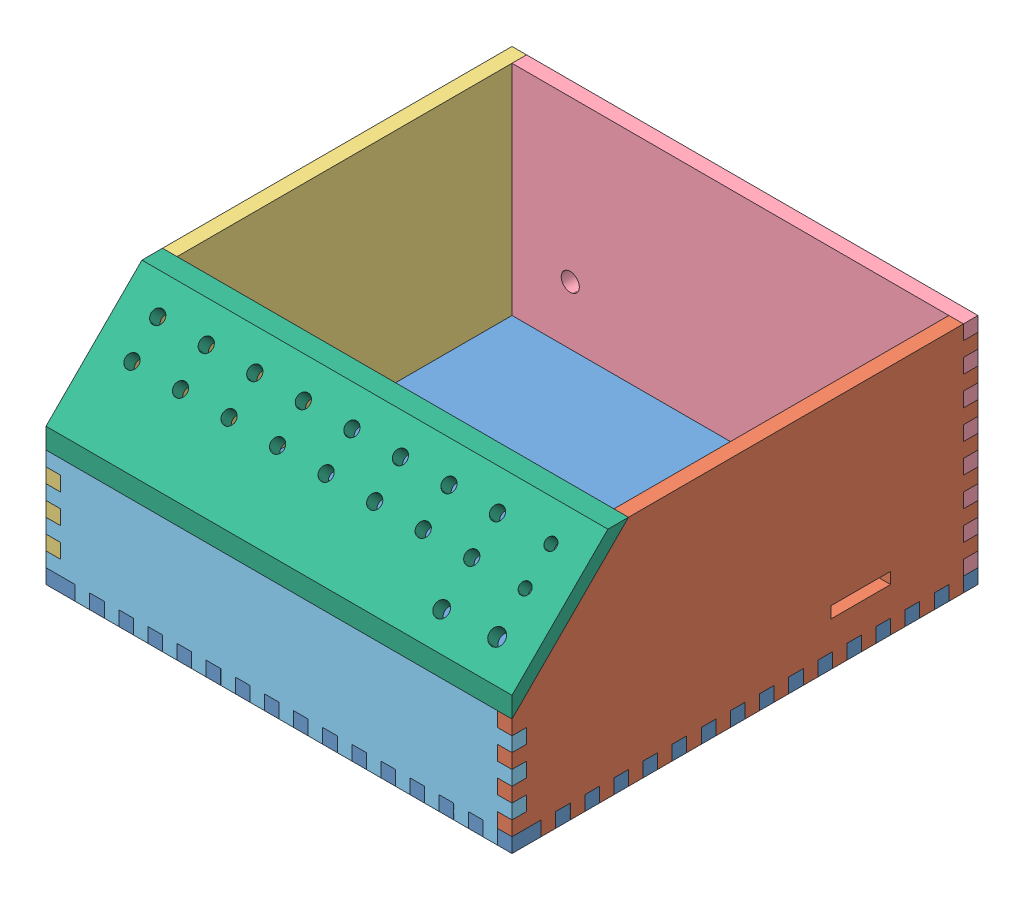
SolidWorks assembly Z80 Box_assembly, configuration Default. Lengths in mm.
Overall size (203.2 106.09 207.69).
6 component instances, 6 part files, 9 mates.
Components (placement in the parent):
- Z80 Box_base-1: Z80 Box_base [Default] at (-24.3287 94.5971 262.4406) size (203.2 6.35 203.2)
- Z80 Box_side_right-1: Z80 Box_side_right [Default] at (172.5213 94.5971 262.4406) size (6.35 101.6 203.2)
- Z80 Box_side_left-1: Z80 Box_side_left [Default] at (-17.9787 94.5971 262.4406) size (6.35 101.6 203.2)
- Z80 Box_back-1: Z80 Box_back [Default] at (178.8713 94.5971 65.5906) x (0 0 -1) z (1 0 0) size (6.35 101.6 203.2)
- Z80 Box_front_bottom-1: Z80 Box_front_bottom [Default] at (-24.3287 94.5971 256.0906) size (203.2 57.15 6.35)
- Z80 Box_front_top-2: Z80 Box_front_top [Default] at (-24.3287 145.3971 262.4406) x (1 0 0) z (0 0.707107 0.707107) size (203.2 71.84 6.35)
Mates (geometry in assembly coordinates):
- Coincident1: coincident aligned: line of Z80 Box_base-1 through (178.8713 100.9471 262.4406) axis (-1 0 0); line of Z80 Box_side_right-1 through (178.8713 100.9471 262.4406) axis (-1 0 0)
- Coincident2: coincident anti-aligned: line of Z80 Box_base-1 through (178.8713 94.5971 249.7406) axis (0 1 0); line of Z80 Box_side_right-1 through (178.8713 100.9471 249.7406) axis (0 -1 0)
- Coincident3: coincident aligned: line of Z80 Box_base-1 through (-24.3287 100.9471 59.2406) axis (1 0 0); line of Z80 Box_side_left-1 through (-24.3287 100.9471 59.2406) axis (1 0 0)
- Coincident9: coincident anti-aligned: line of Z80 Box_side_left-1 through (-17.9787 189.8471 59.2406) axis (0 1 0); line of Z80 Box_back-1 through (-17.9787 196.1971 59.2406) axis (0 -1 0)
- Coincident10: coincident anti-aligned: line of Z80 Box_side_right-1 through (178.8713 196.1971 65.5906) axis (0 -1 0); line of Z80 Box_back-1 through (178.8713 189.8471 65.5906) axis (0 1 0)
- Coincident15: coincident aligned: line of Z80 Box_side_right-1 through (178.8713 107.2971 256.0906) axis (0 0 1); line of Z80 Box_front_bottom-1 through (178.8713 107.2971 256.0906) axis (0 0 1)
- Coincident16: coincident aligned: line of Z80 Box_base-1 through (166.1713 94.5971 256.0906) axis (1 0 0); line of Z80 Box_front_bottom-1 through (166.1713 94.5971 256.0906) axis (1 0 0)
- Coincident17: coincident aligned: line of Z80 Box_side_right-1 through (178.8713 145.3971 262.4406) axis (0 0.707107 -0.707107); line of Z80 Box_front_top-2 through (178.8713 145.3971 262.4406) axis (0 0.707107 -0.707107)
- Coincident18: coincident: point of Z80 Box_side_left-1; point of Z80 Box_front_top-2
